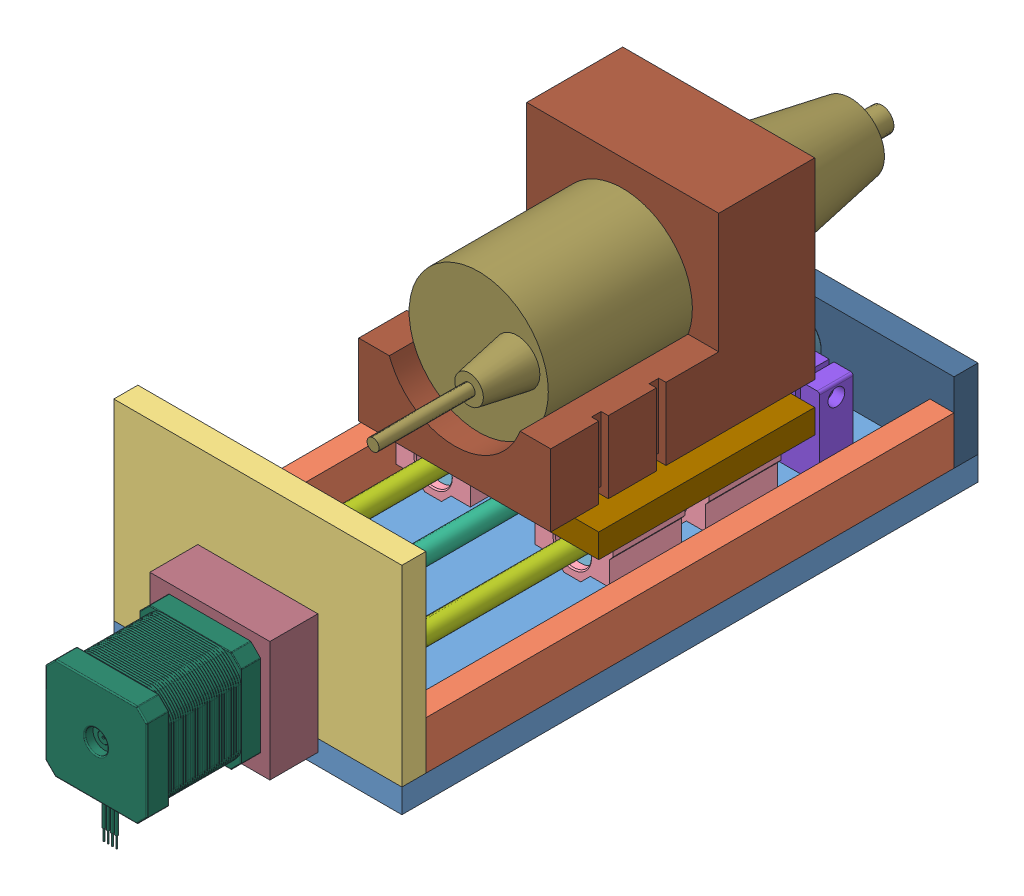
SolidWorks assembly MyDremmelTotalAssem, configuration Default. Lengths in mm.
Overall size (120 141.99 327.4).
33 component instances, 15 part files, 64 mates.
Components (placement in the parent):
- DremmelBoxBack-1: DremmelBoxBack [Default] at origin size (120 10 240)
- DremmelBoxSide-1: DremmelBoxSide [Default] at (0 10 -230) x (0 1 0) z (1 0 0) size (20 220 10)
- DremmelBoxSide-2: DremmelBoxSide [Default] at (110 10 -230) x (0 1 0) z (1 0 0) size (20 220 10)
- DremmelBoxTop-2: DremmelBoxTop [Default] at (0 10 -10) x (1 0 0) z (0 -1 0) size (120 10 80)
- Ball Bearing Assemby-1: Ball Bearing Assemby [Default] at (48 41 -172) x (-1 0 0) z (0 0 1) size (34 21.75 30)
  - Ball Bearing Slider-1: Ball Bearing Slider [Default] at origin size (34 21.75 30)
  - Ball Bearing Imaginary Inlay-1: Ball Bearing Imaginary Inlay [Default] at (17 11 3.5) size (15 15 23)
- Ball Bearing Assemby-2: Ball Bearing Assemby [Default] at (48 41 -132) x (-1 0 0) z (0 0 1) size (34 21.75 30)
  - Ball Bearing Slider-1: Ball Bearing Slider [Default] at origin size (34 21.75 30)
  - Ball Bearing Imaginary Inlay-1: Ball Bearing Imaginary Inlay [Default] at (17 11 3.5) size (15 15 23)
- Ball Bearing Assemby-3: Ball Bearing Assemby [Default] at (106 41 -172) x (-1 0 0) z (0 0 1) size (34 21.75 30)
  - Ball Bearing Slider-1: Ball Bearing Slider [Default] at origin size (34 21.75 30)
  - Ball Bearing Imaginary Inlay-1: Ball Bearing Imaginary Inlay [Default] at (17 11 3.5) size (15 15 23)
- Ball Bearing Assemby-4: Ball Bearing Assemby [Default] at (106 41 -132) x (-1 0 0) z (0 0 1) size (34 21.75 30)
  - Ball Bearing Slider-1: Ball Bearing Slider [Default] at origin size (34 21.75 30)
  - Ball Bearing Imaginary Inlay-1: Ball Bearing Imaginary Inlay [Default] at (17 11 3.5) size (15 15 23)
- SkruvadStång200-1: SkruvadStång200 [По умолчанию] at (60 30 -109.7) x (0 0 -1) z (0.908727 -0.417391 0) size (200 8 8)
- Stång 200mm-1: Stång 200mm [Default] at (89 30 -10) x (0 0 -1) z (0.987596 0.157015 0) size (200 8 8)
- Stånghållare-1: Stånghållare [Default] at (89 30 -24) size (42 33.4 14)
- Stånghållare-2: Stånghållare [Default] at (89 30 -210) size (42 33.4 14)
- Stånghållare-3: Stånghållare [Default] at (31 30 -10) x (-1 0 0) z (0 0 -1) size (42 33.4 14)
- Stånghållare-4: Stånghållare [Default] at (31 30 -196) x (-1 0 0) z (0 0 -1) size (42 33.4 14)
- Stång 200mm-2: Stång 200mm [Default] at (31 30 -210) x (0 0 1) z (0.080523 0.996753 0) size (200 8 8)
- Stånghållare-6: Stånghållare [Default] at (60 30 -196) size (42 33.4 14)
- Stånghållare-7: Stånghållare [Default] at (60 30 -38) size (42 33.4 14)
- DremmelHolderMountPlate-1: DremmelHolderMountPlate [Default] at (10 41 -92) size (100 10 90)
- DremmelBoxBottom-1: DremmelBoxBottom [Default] at (0 10 -240) x (1 0 0) z (0 -1 0) size (120 10 33)
- DremmelHolder-1: DremmelHolder [Default] at (20 51 -192) x (1 0 0) z (0 -1 0) size (80 110 80)
- Dremmel-1: Dremmel [Default] at (60 91 -92) x (0 1 0) z (-1 0 0) size (81.68 298 81.68)
- ZAxisMotorSpacer-1: ZAxisMotorSpacer [Default] at (85 55 20) x (0 -1 0) z (1 0 0) size (50 20 50)
- MotorToRodFastener 5x10mm-1: MotorToRodFastener 5x10mm [По умолчанию] at (60 30 -6.95) x (-0.177004 0.98421 0) z (0 0 1) size (20 21.03 25.5)
- Nema 17  Stepper Motor length 48mm-2: Nema 17  Stepper Motor length 48mm [По умолчанию] at (60 30 67.4) x (-1 0 0) z (0 -1 0) size (42.3 71.6 61.3)
- MotorToRodFastener 5x10mm-3: MotorToRodFastener 5x10mm [По умолчанию] at (60 30 -212.45) x (0.815261 0.579094 0) z (0 0 -1) size (20 21.03 25.5)
Mates (geometry in assembly coordinates):
- Coincident1: coincident: plane of DremmelBoxBack-1 through (0 10 0) normal (0 1 0); plane of DremmelBoxSide-1 through (10 10 -230) normal (0 -1 0)
- Coincident6: coincident: plane of DremmelBoxBack-1 through (0 10 0) normal (-1 0 0); plane of DremmelBoxSide-1 through (0 10 -230) normal (-1 0 0)
- Coincident7: coincident: plane of DremmelBoxBack-1 through (0 10 0) normal (0 1 0); plane of DremmelBoxSide-2 through (120 10 -230) normal (0 -1 0)
- Coincident9: coincident: plane of DremmelBoxBack-1 through (120 10 0) normal (1 0 0); plane of DremmelBoxSide-2 through (120 10 -230) normal (1 0 0)
- Coincident10: coincident: plane of DremmelBoxBack-1 through (0 10 0) normal (0 1 0); plane of DremmelBoxTop-2 through (0 10 0) normal (0 -1 0)
- Coincident11: coincident: plane of DremmelBoxBack-1 through (0 10 0) normal (0 0 1); plane of DremmelBoxTop-2 through (0 10 0) normal (0 0 1)
- Coincident12: coincident: plane of DremmelBoxBack-1 through (0 10 0) normal (-1 0 0); plane of DremmelBoxTop-2 through (0 10 0) normal (-1 0 0)
- Coincident13: coincident: plane of DremmelBoxBack-1 through (0 10 0) normal (0 1 0); plane of Stånghållare-4 through (52 10 -210) normal (0 -1 0)
- Coincident14: coincident: plane of DremmelBoxBack-1 through (0 10 0) normal (0 1 0); plane of Stånghållare-1 through (68 10 -10) normal (0 -1 0)
- Coincident15: coincident: plane of DremmelBoxBack-1 through (0 10 0) normal (0 1 0); plane of Stånghållare-3 through (52 10 -24) normal (0 -1 0)
- Coincident16: coincident: plane of DremmelBoxBack-1 through (0 10 0) normal (0 1 0); plane of Stånghållare-2 through (68 10 -196) normal (0 -1 0)
- Coincident19: coincident: plane of DremmelBoxTop-2 through (0 10 -10) normal (0 0 -1); plane of Stånghållare-3 through (31 30 -10) normal (0 0 1)
- Coincident20: coincident: plane of DremmelBoxTop-2 through (0 10 -10) normal (0 0 -1); plane of Stånghållare-1 through (89 30 -10) normal (0 0 1)
- Coincident21: coincident: plane of DremmelBoxSide-1 through (10 10 -230) normal (1 0 0); plane of Stånghållare-4 through (10 10 -210) normal (-1 0 0)
- Coincident22: coincident: plane of DremmelBoxSide-2 through (110 10 -230) normal (-1 0 0); plane of Stånghållare-2 through (110 10 -196) normal (1 0 0)
- Coincident23: coincident: plane of DremmelBoxSide-1 through (10 10 -230) normal (1 0 0); plane of Stånghållare-3 through (10 10 -24) normal (-1 0 0)
- Coincident24: coincident: plane of DremmelBoxSide-2 through (110 10 -230) normal (-1 0 0); plane of Stånghållare-1 through (110 10 -10) normal (1 0 0)
- Concentric1: concentric: cylinder of Stånghållare-4 through (31 30 -210) axis (0 0 1) radius 4; cylinder of Stång 200mm-2 through (31 30 -10) axis (0 0 -1) radius 4
- Concentric2: concentric: cylinder of Stång 200mm-1 through (89 30 -210) axis (0 0 1) radius 4; cylinder of Stånghållare-2 through (89 30 -196) axis (0 0 -1) radius 4
- Concentric3: concentric: cylinder of Ball Bearing Assemby-3/Ball Bearing Imaginary Inlay-1 through (89 30 -168.5) axis (0 0 1) radius 4.05; cylinder of Stång 200mm-1 through (89 30 -210) axis (0 0 1) radius 4
- Concentric4: concentric: cylinder of Ball Bearing Assemby-4/Ball Bearing Imaginary Inlay-1 through (89 30 -128.5) axis (0 0 1) radius 4.05; cylinder of Stång 200mm-1 through (89 30 -210) axis (0 0 1) radius 4
- Concentric5: concentric: cylinder of Ball Bearing Assemby-1/Ball Bearing Imaginary Inlay-1 through (31 30 -168.5) axis (0 0 1) radius 4.05; cylinder of Stång 200mm-2 through (31 30 -10) axis (0 0 -1) radius 4
- Concentric6: concentric: cylinder of Ball Bearing Assemby-2/Ball Bearing Imaginary Inlay-1 through (31 30 -128.5) axis (0 0 1) radius 4.05; cylinder of Stång 200mm-2 through (31 30 -10) axis (0 0 -1) radius 4
- Coincident27: coincident: plane of DremmelBoxBack-1 through (0 10 0) normal (0 1 0); plane of Stånghållare-7 through (39 10 -24) normal (0 -1 0)
- Coincident28: coincident: plane of Stånghållare-1 through (89 30 -24) normal (0 0 -1); plane of Stånghållare-7 through (60 30 -24) normal (0 0 1)
- Coincident29: coincident: plane of DremmelBoxBack-1 through (0 10 0) normal (0 1 0); plane of Stånghållare-6 through (39 10 -182) normal (0 -1 0)
- Coincident30: coincident: plane of Stånghållare-2 through (89 30 -196) normal (0 0 1); plane of Stånghållare-6 through (60 30 -196) normal (0 0 -1)
- Concentric7: concentric: cylinder of SkruvadStång200-1 through (60 30 -9.7) axis (0 0 1) radius 4; cylinder of Stånghållare-6 through (60 30 -182) axis (0 0 -1) radius 4
- Concentric8: concentric: cylinder of SkruvadStång200-1 through (60 30 -9.7) axis (0 0 1) radius 4; cylinder of Stånghållare-7 through (60 30 -24) axis (0 0 -1) radius 4
- Coincident31: coincident: plane of Ball Bearing Assemby-1/Ball Bearing Slider-1 through (22 41 -142) normal (0 1 0); plane of DremmelHolderMountPlate-1 through (10 41 -92) normal (0 -1 0)
- Coincident32: coincident: plane of Ball Bearing Assemby-3/Ball Bearing Slider-1 through (80 41 -142) normal (0 1 0); plane of DremmelHolderMountPlate-1 through (10 41 -92) normal (0 -1 0)
- Coincident33: coincident: plane of Ball Bearing Assemby-2/Ball Bearing Slider-1 through (22 41 -102) normal (0 1 0); plane of DremmelHolderMountPlate-1 through (10 41 -92) normal (0 -1 0)
- Parallel1: parallel: plane of Ball Bearing Assemby-4/Ball Bearing Slider-1 through (98 41 -102) normal (0 1 0); plane of DremmelHolderMountPlate-1 through (10 41 -92) normal (0 -1 0)
- Distance1: distance = 10 mm: plane of Ball Bearing Assemby-2/Ball Bearing Slider-1 through (48 41 -102) normal (0 0 1); plane of DremmelHolderMountPlate-1 through (10 51 -92) normal (0 0 1)
- Distance2: distance = 10 mm: plane of Ball Bearing Assemby-4/Ball Bearing Slider-1 through (106 41 -102) normal (0 0 1); plane of DremmelHolderMountPlate-1 through (10 51 -92) normal (0 0 1)
- Distance3: distance = 10 mm: plane of Ball Bearing Assemby-1/Ball Bearing Slider-1 through (48 41 -172) normal (0 0 -1); plane of DremmelHolderMountPlate-1 through (10 51 -182) normal (0 0 -1)
- Distance4: distance = 10 mm: plane of Ball Bearing Assemby-3/Ball Bearing Slider-1 through (106 41 -172) normal (0 0 -1); plane of DremmelHolderMountPlate-1 through (10 51 -182) normal (0 0 -1)
- Distance5: distance = 4 mm: plane of DremmelHolderMountPlate-1 through (110 51 -92) normal (1 0 0); plane of Ball Bearing Assemby-4/Ball Bearing Slider-1 through (106 41 -102) normal (1 0 0)
- Coincident42: coincident: plane of DremmelBoxBack-1 through (120 10 0) normal (1 0 0); plane of DremmelBoxBottom-1 through (120 10 -230) normal (1 0 0)
- Coincident44: coincident: plane of DremmelBoxBack-1 through (0 10 0) normal (0 1 0); plane of DremmelBoxBottom-1 through (0 10 -230) normal (0 -1 0)
- Coincident45: coincident: plane of DremmelBoxSide-2 through (120 10 -230) normal (0 0 -1); plane of DremmelBoxBottom-1 through (0 10 -230) normal (0 0 1)
- LimitDistance1: limit distance = 0 mm: plane of DremmelHolderMountPlate-1 through (10 51 -182) normal (0 0 -1); plane of Stånghållare-6 through (60 30 -182) normal (0 0 1)
- Coincident49: coincident: plane of DremmelBoxSide-1 through (10 10 -230) normal (0 0 -1); plane of DremmelBoxBottom-1 through (0 10 -230) normal (0 0 1)
- Coincident51: coincident: plane of DremmelBoxSide-1 through (10 10 -10) normal (0 0 1); plane of DremmelBoxTop-2 through (0 10 -10) normal (0 0 -1)
- Coincident52: coincident: plane of DremmelHolderMountPlate-1 through (10 51 -92) normal (0 1 0); plane of DremmelHolder-1 through (100 51 -82) normal (0 -1 0)
- Distance8: distance = 10 mm: plane of DremmelHolder-1 through (100 81 -82) normal (0 0 1); plane of DremmelHolderMountPlate-1 through (10 51 -92) normal (0 0 1)
- Distance9: distance = 10 mm: plane of DremmelHolder-1 through (20 51 -192) normal (-1 0 0); plane of DremmelHolderMountPlate-1 through (10 51 -92) normal (-1 0 0)
- Coincident55: coincident: plane of DremmelHolder-1 through (60 91 -182) normal (0 0 1); plane of Dremmel-1 through (60 91 -182) normal (0 0 -1)
- Concentric9: concentric: circle of DremmelHolder-1; cone of Dremmel-1 through (60 91 -182) axis (0 0 -1)
- Concentric10: concentric: circle of DremmelBoxTop-2; circle of ZAxisMotorSpacer-1
- Concentric11: concentric: cylinder of SkruvadStång200-1 through (60 30 -9.7) axis (0 0 1) radius 4; cylinder of MotorToRodFastener 5x10mm-1 through (60 30 -1.3132) axis (0 0 1) radius 5
- Distance11: distance = 10 mm: plane of MotorToRodFastener 5x10mm-1 through (60 30 -19.7) normal (0 0 -1); plane of SkruvadStång200-1 through (60 30 -9.7) normal (0 0 1)
- Concentric12: concentric: cylinder of ZAxisMotorSpacer-1 through (60 30 30) axis (0 0 -1) radius 12.5; cylinder of MotorToRodFastener 5x10mm-1 through (60 30 5.8) axis (0 0 -1) radius 10
- Coincident61: coincident: plane of DremmelBoxTop-2 through (0 10 0) normal (0 0 1); plane of ZAxisMotorSpacer-1 through (85 55 0) normal (0 0 -1)
- Coincident63: coincident: plane of ZAxisMotorSpacer-1 through (85 55 20) normal (0 0 1); plane of Nema 17  Stepper Motor length 48mm-2 through (60 30 20) normal (0 0 -1)
- Concentric13: concentric: cylinder of MotorToRodFastener 5x10mm-1 through (60 30 5.8) axis (0 0 -1) radius 2.5; cylinder of Nema 17  Stepper Motor length 48mm-2 through (60 30 -4.2) axis (0 0 1) radius 2.5
- Parallel3: parallel: plane of ZAxisMotorSpacer-1 through (35 55 0) normal (-1 0 0); plane of Nema 17  Stepper Motor length 48mm-2 through (38.85 30 28.2) normal (-1 0 0)
- Coincident65: coincident: plane of DremmelBoxTop-2 through (0 10 -10) normal (0 0 -1); plane of Stång 200mm-1 through (89 30 -10) normal (0 0 1)
- Coincident67: coincident: plane of Stånghållare-4 through (31 30 -210) normal (0 0 -1); plane of Stång 200mm-2 through (31 30 -210) normal (0 0 -1)
- Coincident68: coincident: plane of DremmelBoxTop-2 through (0 10 -10) normal (0 0 -1); plane of Stång 200mm-2 through (31 30 -10) normal (0 0 1)
- Distance12: distance = 10 mm: plane of Nema 17  Stepper Motor length 48mm-2 through (60 30 -4.2) normal (0 0 -1); plane of MotorToRodFastener 5x10mm-1 through (60 30 5.8) normal (0 0 1)
- Coincident74: coincident: plane of Stång 200mm-1 through (89 30 -210) normal (0 0 -1); plane of Stånghållare-2 through (89 30 -210) normal (0 0 -1)
- Concentric14: concentric: cylinder of SkruvadStång200-1 through (60 30 -9.7) axis (0 0 1) radius 4; cylinder of MotorToRodFastener 5x10mm-3 through (60 30 -218.0868) axis (0 0 -1) radius 5
- Distance13: distance = 10 mm: plane of MotorToRodFastener 5x10mm-3 through (60 30 -199.7) normal (0 0 1); plane of SkruvadStång200-1 through (61.6696 33.6349 -209.7) normal (0 0 -1)
